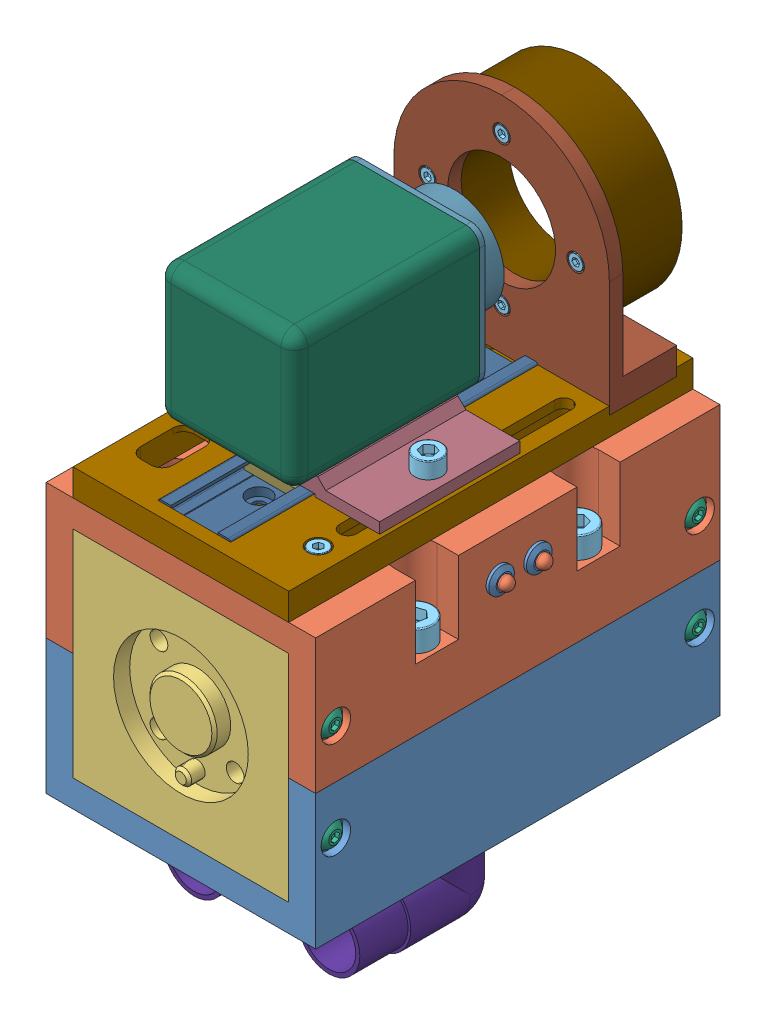
SolidWorks assembly Montagem, configuration Default. Lengths in mm.
Overall size (111.6 226.5 190.87).
85 component instances, 27 part files, 54 mates.
Components (placement in the parent):
- Conjunto-1: Conjunto [Default] at (26.1796 1.0636 35.9345) size (100.24 100 190.87)
  - Estrutura_bottom-1: Estrutura_bottom [Default] at (-19.0494 -42.1119 38.6623) size (100 50 150)
  - Estrutura_top-1: Estrutura_top [Default] at (-19.0494 47.8881 38.6623) x (-1 0 0) z (0 0 1) size (100 50 150)
  - Acoplamento_robot_50mm-1: Acoplamento_robot_50mm [Default] at (-19.0494 -2.1119 23.6623) size (80 80 15)
  - Acplamento_garra-1: Acplamento_garra [Default] at (-19.0494 -2.1119 -96.3377) size (80 80 102.04)
  - Socket Head Cap Screw_ISO-4: Socket Head Cap Screw_ISO [ISO 4762 M8 x 40 --- 28C] at (22.9506 28.8881 -6.3377) x (0 -1 0) z (-0.319372 0 -0.947629) size (48 13 13)
  - Socket Head Cap Screw_ISO-5: Socket Head Cap Screw_ISO [ISO 4762 M8 x 40 --- 28C] at (-61.0494 28.8881 -6.3377) x (0 -1 0) z (0.245168 0 0.96948) size (48 13 13)
  - Socket Head Cap Screw_ISO-6: Socket Head Cap Screw_ISO [ISO 4762 M8 x 40 --- 28C] at (22.9506 28.8881 -66.3377) x (0 -1 0) z (0.971794 0 -0.235832) size (48 13 13)
  - Socket Head Cap Screw_ISO-7: Socket Head Cap Screw_ISO [ISO 4762 M8 x 40 --- 28C] at (-61.0494 28.8881 -66.3377) x (0 -1 0) z (0 0 1) size (48 13 13)
  - Socket Button Head Screw_ISO-1: Socket Button Head Screw_ISO [ISO 7380 - M5 x 16 --- 16C] at (-68.7994 15.8881 -103.8377) x (1 0 0) z (0 -0.335428 0.942066) size (18.75 9.5 9.5)
  - Socket Button Head Screw_ISO-2: Socket Button Head Screw_ISO [ISO 7380 - M5 x 16 --- 16C] at (-68.7994 -20.1119 -103.8377) size (18.75 9.5 9.5)
  - Socket Button Head Screw_ISO-3: Socket Button Head Screw_ISO [ISO 7380 - M5 x 16 --- 16C] at (-68.7994 -20.1119 31.1623) size (18.75 9.5 9.5)
  - Socket Button Head Screw_ISO-4: Socket Button Head Screw_ISO [ISO 7380 - M5 x 16 --- 16C] at (-68.7994 15.8881 31.1623) size (18.75 9.5 9.5)
  - Socket Button Head Screw_ISO-5: Socket Button Head Screw_ISO [ISO 7380 - M5 x 16 --- 16C] at (30.7006 -20.1119 -103.8377) x (-1 0 0) z (0 -0.924225 -0.381849) size (18.75 9.5 9.5)
  - Socket Button Head Screw_ISO-6: Socket Button Head Screw_ISO [ISO 7380 - M5 x 16 --- 16C] at (30.7006 15.8881 31.1623) x (-1 0 0) z (0 -0.924225 -0.381849) size (18.75 9.5 9.5)
  - Socket Button Head Screw_ISO-7: Socket Button Head Screw_ISO [ISO 7380 - M5 x 16 --- 16C] at (30.7006 15.8881 -103.8377) x (-1 0 0) z (0 -0.924225 -0.381849) size (18.75 9.5 9.5)
  - Socket Button Head Screw_ISO-8: Socket Button Head Screw_ISO [ISO 7380 - M5 x 16 --- 16C] at (30.7006 -20.1119 31.1623) x (-1 0 0) z (0 -0.924225 -0.381849) size (18.75 9.5 9.5)
  - Socket Button Head Screw_ISO-9: Socket Button Head Screw_ISO [ISO 7380 - M5 x 16 --- 16C] at (-1.0494 -49.8619 31.1623) x (0 1 0) z (-0.188342 0 0.982104) size (18.75 9.5 9.5)
  - Socket Button Head Screw_ISO-10: Socket Button Head Screw_ISO [ISO 7380 - M5 x 16 --- 16C] at (-37.0494 -49.8619 -103.8377) x (0 1 0) z (-0.319462 0 0.947599) size (18.75 9.5 9.5)
  - Socket Button Head Screw_ISO-11: Socket Button Head Screw_ISO [ISO 7380 - M5 x 16 --- 16C] at (-1.0494 -49.8619 -103.8377) x (0 1 0) z (0.485773 0 0.874085) size (18.75 9.5 9.5)
  - Socket Button Head Screw_ISO-12: Socket Button Head Screw_ISO [ISO 7380 - M5 x 16 --- 16C] at (-37.0494 -49.8619 31.1623) x (0 1 0) z (-0.266822 0 0.963746) size (18.75 9.5 9.5)
  - Socket Button Head Screw_ISO-13: Socket Button Head Screw_ISO [ISO 7380 - M5 x 16 --- 16C] at (-1.0494 47.6381 -103.8377) x (0 -1 0) z (0 0 1) size (18.75 9.5 9.5)
  - Socket Button Head Screw_ISO-14: Socket Button Head Screw_ISO [ISO 7380 - M5 x 16 --- 16C] at (-37.1275 47.6381 -103.4453) x (0 -1 0) z (0 0 1) size (18.75 9.5 9.5)
  - Socket Button Head Screw_ISO-15: Socket Button Head Screw_ISO [ISO 7380 - M5 x 16 --- 16C] at (-37.0494 47.6381 31.1623) x (0 -1 0) z (0 0 1) size (18.75 9.5 9.5)
  - Socket Button Head Screw_ISO-16: Socket Button Head Screw_ISO [ISO 7380 - M5 x 16 --- 16C] at (-1.0494 47.6381 31.1623) x (0 -1 0) z (0 0 1) size (18.75 9.5 9.5)
  - PCB-1: PCB [Default] at (-19.0494 13.3881 -36.3377) size (66 1.5 80)
  - Slotted Cheese Head Screw_ISO-4: Slotted Cheese Head Screw_ISO [ISO 1207 - M3 x 8 --- 8C] at (10.4506 11.3881 -66.3377) x (0 1 0) z (0.99688 0 -0.078934) size (10.01 5.5 5.5)
  - Slotted Cheese Head Screw_ISO-1: Slotted Cheese Head Screw_ISO [ISO 1207 - M3 x 8 --- 8C] at (10.4506 11.3881 -6.3377) x (0 1 0) z (-0.0255 0 0.999675) size (10.01 5.5 5.5)
  - Slotted Cheese Head Screw_ISO-2: Slotted Cheese Head Screw_ISO [ISO 1207 - M3 x 8 --- 8C] at (-48.5494 11.3881 -66.3377) x (0 1 0) z (0.247102 0 -0.96899) size (10.01 5.5 5.5)
  - Slotted Cheese Head Screw_ISO-3: Slotted Cheese Head Screw_ISO [ISO 1207 - M3 x 8 --- 8C] at (-48.5494 11.3881 -6.3377) x (0 1 0) z (0.728633 0 -0.684905) size (10.01 5.5 5.5)
- Sistema_visao-1: Sistema_visao [Default] at (9.6589 51.4266 -3.453) x (-1 0 0) z (0 0 -1) size (80 99 174.57)
  - Apoio_sistema_visao-1: Apoio_sistema_visao [Default] at (2.5288 -2.475 -3.0498) size (80 10 150)
  - Calha_deslizante_27mm-1: Calha_deslizante_27mm [Default] at (2.5288 -0.475 40.9502) x (1 0 0) z (0 1 0) size (27 114 8.7)
  - Apoio_iluminacaoLEDs-1: Apoio_iluminacaoLEDs [Default] at (2.5288 47.525 45.9502) size (80 83 83.14)
  - Socket Head Cap Screw_ISO-1: Socket Head Cap Screw_ISO [ISO 4762 M4 x 12 --- 12C] at (-19.4712 14.525 55.9502) x (0 -1 0) z (-0.2501 0 -0.96822) size (16 7 7)
  - Socket Head Cap Screw_ISO-2: Socket Head Cap Screw_ISO [ISO 4762 M4 x 12 --- 12C] at (24.5288 14.525 55.9502) x (0 -1 0) z (-0.380763 0 -0.924673) size (16 7 7)
  - Carro_deslizante_27mm-1: Carro_deslizante_27mm [Default] at (2.5288 -0.525 -23.2951) x (1 0 0) z (0 1 0) size (23.9 40 5.35)
  - Apoio_camara_27mm-1: Apoio_camara_27mm [Default] at (2.5288 7.975 -43.2951) x (-1 0 0) z (0 0 -1) size (54 7 52)
  - Camara-1: Camara [Default] at (-7.4062 36.6309 -9.1632) size (50.8 57.8 84.8)
    - Encaixe_lente-1: Encaixe_lente [Default] at (9.935 10.7441 16.5114) size (50.8 50.8 16.1)
    - Carapaca-1: Carapaca [Default] at (9.935 10.7441 -17.8386) size (50.8 57.8 68.7)
  - Socket Button Head Screw_ISO-1: Socket Button Head Screw_ISO [ISO 7380 - M6 x 10 --- 10C] at (2.5288 9.575 -1.2951) x (0 1 0) z (-0.765429 0 0.643521) size (13.3 10.5 10.5)
  - Socket Button Head Screw_ISO-2: Socket Button Head Screw_ISO [ISO 7380 - M6 x 10 --- 10C] at (2.5288 9.575 -23.2951) x (0 1 0) z (0.299016 0 -0.954248) size (13.3 10.5 10.5)
  - Socket Button Head Screw_ISO-3: Socket Button Head Screw_ISO [ISO 7380 - M4 x 8 --- 8C] at (2.5288 5.275 -13.2951) x (0 1 0) z (-0.212483 0 0.977165) size (10.2 7.6 7.6)
  - Socket Button Head Screw_ISO-4: Socket Button Head Screw_ISO [ISO 7380 - M4 x 8 --- 8C] at (2.5288 5.275 -33.2951) x (0 1 0) z (-0.150761 0 0.98857) size (10.2 7.6 7.6)
  - Socket Head Cap Screw_ISO-3: Socket Head Cap Screw_ISO [ISO 4762 M6 x 12 --- 12C] at (-28.4712 17.975 -17.2951) x (0 -1 0) z (-0.981232 0 0.192829) size (18 10 10)
  - Hex Nut GradeC_ISO-1: Hex Nut GradeC_ISO [Hexagon Nut ISO - 4034 - M6 - C] at (-28.4712 4.025 -17.2951) x (1 0 0) z (0 1 0) size (10 11.55 6.1)
  - Socket Button Head Screw_ISO-6: Socket Button Head Screw_ISO [ISO 7380 - M4 x 12 --- 12C] at (2.5288 2.725 10.9502) x (0 -1 0) z (0.860915 0 -0.508749) size (14.2 7.6 7.6)
- Socket Head Cap Screw_ISO-2: Socket Head Cap Screw_ISO [ISO 4762 M4 x 16 --- 16N] at (38.1302 58.9516 54.5968) x (0 -1 0) z (-0.712267 0 0.701908) size (20 7 7)
- Socket Head Cap Screw_ISO-3: Socket Head Cap Screw_ISO [ISO 4762 M4 x 12 --- 12N] at (-23.8698 55.9516 -55.4032) x (0 -1 0) z (0 0 1) size (16 7 7)
- Conector_electrico-1: Conector_electrico [Default] at (32.0302 -46.0484 4.4968) x (0 0 1) z (1 0 0) size (52.9 41.5 25.6)
- Conector_electrico-2: Conector_electrico [Default] at (-17.9698 -46.0484 4.4968) x (0 0 1) z (1 0 0) size (52.9 41.5 25.6)
- Socket Head Cap Screw_ISO-4: Socket Head Cap Screw_ISO [ISO 4762 M2.5 x 6 --- 6N] at (22.2302 -51.0484 14.4968) x (0 1 0) z (-0.277944 0 0.960597) size (8.5 4.5 4.5)
- Socket Head Cap Screw_ISO-5: Socket Head Cap Screw_ISO [ISO 4762 M2.5 x 6 --- 6N] at (-7.9698 -51.0484 -5.3032) x (0 1 0) z (-0.277944 0 0.960597) size (8.5 4.5 4.5)
- Socket Head Cap Screw_ISO-6: Socket Head Cap Screw_ISO [ISO 4762 M2.5 x 6 --- 6N] at (22.2302 -51.0484 -5.3032) x (0 1 0) z (-0.277944 0 0.960597) size (8.5 4.5 4.5)
- Socket Head Cap Screw_ISO-7: Socket Head Cap Screw_ISO [ISO 4762 M2.5 x 6 --- 6N] at (42.0302 -51.0484 14.4968) x (0 1 0) z (-0.277944 0 0.960597) size (8.5 4.5 4.5)
- Socket Head Cap Screw_ISO-8: Socket Head Cap Screw_ISO [ISO 4762 M2.5 x 6 --- 6N] at (42.0302 -51.0484 -5.3032) x (0 1 0) z (-0.277944 0 0.960597) size (8.5 4.5 4.5)
- Socket Head Cap Screw_ISO-9: Socket Head Cap Screw_ISO [ISO 4762 M2.5 x 6 --- 6N] at (-7.9698 -51.0484 14.4968) x (0 1 0) z (-0.277944 0 0.960597) size (8.5 4.5 4.5)
- Socket Head Cap Screw_ISO-10: Socket Head Cap Screw_ISO [ISO 4762 M2.5 x 6 --- 6N] at (-27.7698 -51.0484 -5.3032) x (0 1 0) z (-0.277944 0 0.960597) size (8.5 4.5 4.5)
- Socket Head Cap Screw_ISO-11: Socket Head Cap Screw_ISO [ISO 4762 M2.5 x 6 --- 6N] at (-27.7698 -51.0484 14.4968) x (0 1 0) z (-0.277944 0 0.960597) size (8.5 4.5 4.5)
- Anel-1: Anel [Default] at (7.1302 98.9516 -49.4032) x (-1 0 0) z (0 0 -1) size (72 72 26)
- Socket Head Cap Screw_ISO-12: Socket Head Cap Screw_ISO [ISO 4762 M3 x 5 --- 5N] at (7.1302 126.4516 -44.4032) x (0 0 -1) z (0.931779 0.363027 0) size (8 5.5 5.5)
- Socket Head Cap Screw_ISO-13: Socket Head Cap Screw_ISO [ISO 4762 M3 x 5 --- 5N] at (7.1302 71.4516 -44.4032) x (0 0 -1) z (0.268788 -0.963199 0) size (8 5.5 5.5)
- Socket Head Cap Screw_ISO-14: Socket Head Cap Screw_ISO [ISO 4762 M3 x 5 --- 5N] at (-20.3698 98.9516 -44.4032) x (0 0 -1) z (0.3353 0.942111 0) size (8 5.5 5.5)
- Socket Head Cap Screw_ISO-15: Socket Head Cap Screw_ISO [ISO 4762 M3 x 5 --- 5N] at (34.6302 98.9516 -44.4032) x (0 0 -1) z (0.192392 -0.981318 0) size (8 5.5 5.5)
- LED_8mm-1: LED_8mm [Default] at (52.2812 31.651 9.4625) x (0 0.897449 0.441118) z (0 0.441118 -0.897449) size (9.5 23.85 9.5)
  - Suporte_LED-1: Suporte_LED [Default] at (0.8006 -5.901 3.5866) size (9.5 12.75 9.5)
  - LED-1: LED [Default] at (0.8006 7.449 3.5866) size (5 3.1 5)
  - Conexao-1: Conexao [Default] at (0.8006 -7.901 3.5866) x (0.063421 0 0.997987) z (-0.997987 0 0.063421) size (8 8 8)
- LED_8mm-2: LED_8mm [Default] at (52.2812 33.4745 -3.7594) x (0 0.996003 -0.089314) z (0 -0.089314 -0.996003) size (9.5 23.85 9.5)
  - Suporte_LED-1: Suporte_LED [Default] at (0.8006 -5.901 3.5866) size (9.5 12.75 9.5)
  - LED-1: LED [Default] at (0.8006 7.449 3.5866) size (5 3.1 5)
  - Conexao-1: Conexao [Default] at (0.8006 -7.901 3.5866) x (0.063421 0 0.997987) z (-0.997987 0 0.063421) size (8 8 8)
- Carapaca_topo-1: Carapaca_topo [Default] at (7.1302 48.9516 -0.4032) size (84 95 154) (hidden)
- Conjunto_sensor-1: Conjunto_sensor [Default] at (9.3235 134.4469 21.3822) x (0 0 -1) z (1 0 0) size (38 25.6 39) (hidden)
  - Placa-1: Placa [Default] at (0.0753 1.0047 -1.4363) x (0 0 -1) z (-1 0 0) size (19.9 1.5 22.1)
  - Sensor-1: Sensor [Default] at (0.0753 1.9047 -0.3263) x (0 0 1) z (-1 0 0) size (15.5 18 15.5)
  - Base-1: Base [Default] at (-4.3747 -5.4953 -1.4863) size (38 9.5 39)
  - Tampa2-1: Tampa2 [Default] at (-4.3747 13.0047 -1.4863) x (1 0 0) z (0 0 -1) size (38 15.5 27)
  - LED_8mm-1: LED_8mm [Default] at (-16.7253 10.1557 0.0871) size (9.5 23.85 9.5)
    - Suporte_LED-1: Suporte_LED [Default] at (0.8006 -5.901 3.5866) size (9.5 12.75 9.5)
    - LED-1: LED [Default] at (0.8006 7.449 3.5866) size (5 3.1 5)
    - Conexao-1: Conexao [Default] at (0.8006 -7.901 3.5866) x (0.063421 0 0.997987) z (-0.997987 0 0.063421) size (8 8 8)
- Ventoinha-1: Ventoinha [Default] at (-46.8698 18.9516 -0.4032) x (0 1 0) z (1 0 0) size (25 25 10)
- Socket Head Cap Screw_ISO-17: Socket Head Cap Screw_ISO [ISO 4762 M2.5 x 16 --- 16C] at (-49.3698 28.9516 9.5968) x (1 0 0) z (0 0.619223 0.785215) size (18.5 4.5 4.5)
Mates (geometry in assembly coordinates):
- Concentric1: concentric aligned: cylinder of Conjunto-1/Estrutura_top-1 through (-23.8698 48.9516 -55.4032) axis (0 1 0) radius 1.65; cylinder of Sistema_visao-1/Apoio_sistema_visao-1 through (-23.8698 55.9516 -55.4032) axis (0 1 0) radius 2.4
- Concentric2: concentric aligned: cylinder of Conjunto-1/Estrutura_top-1 through (38.1302 48.9516 54.5968) axis (0 1 0) radius 1.65; cylinder of Sistema_visao-1/Apoio_sistema_visao-1 through (38.1302 58.9516 54.5968) axis (0 1 0) radius 2.4
- Coincident1: coincident anti-aligned: plane of Conjunto-1/Estrutura_top-1 through (57.1302 48.9516 -75.4032) normal (0 1 0); plane of Sistema_visao-1/Apoio_sistema_visao-1 through (47.1302 48.9516 -75.4032) normal (0 -1 0)
- Concentric3: concentric aligned: cylinder of Conjunto-1/Estrutura_top-1 through (38.1302 48.9516 54.5968) axis (0 1 0) radius 1.65; cylinder of Socket Head Cap Screw_ISO-2 through (38.1302 90.7016 54.5968) axis (0 1 0) radius 2
- Concentric4: concentric aligned: cylinder of Conjunto-1/Estrutura_top-1 through (-23.8698 48.9516 -55.4032) axis (0 1 0) radius 1.65; cylinder of Socket Head Cap Screw_ISO-3 through (-23.8698 87.7016 -55.4032) axis (0 1 0) radius 2
- Coincident2: coincident anti-aligned: plane of Sistema_visao-1/Apoio_sistema_visao-1 through (-26.2698 51.9516 -55.4032) normal (0 1 0); plane of Socket Head Cap Screw_ISO-3 through (-20.3698 51.9516 -55.4032) normal (0 -1 0)
- Coincident3: coincident anti-aligned: plane of Sistema_visao-1/Apoio_sistema_visao-1 through (35.7302 54.9516 54.5968) normal (0 1 0); plane of Socket Head Cap Screw_ISO-2 through (40.5869 54.9516 57.0898) normal (0 -1 0)
- Concentric7: concentric aligned: cylinder of Conjunto-1/Estrutura_bottom-1 through (-7.9698 -51.0484 -5.3032) axis (0 -1 0) radius 1.025; cylinder of Conector_electrico-2 through (-7.9698 -48.5484 -5.3032) axis (0 -1 0) radius 1.35
- Concentric9: concentric aligned: cylinder of Conjunto-1/Estrutura_bottom-1 through (-27.7698 -51.0484 14.4968) axis (0 -1 0) radius 1.025; cylinder of Conector_electrico-2 through (-27.7698 -48.5484 14.4968) axis (0 -1 0) radius 1.35
- Coincident4: coincident anti-aligned: plane of Conjunto-1/Estrutura_bottom-1 through (-32.8698 -46.0484 -15.4032) normal (0 -1 0); plane of Conector_electrico-2 through (-5.1698 -46.0484 -8.3032) normal (0 1 0)
- Concentric10: concentric aligned: cylinder of Conjunto-1/Estrutura_bottom-1 through (42.0302 -51.0484 -5.3032) axis (0 -1 0) radius 1.025; cylinder of Conector_electrico-1 through (42.0302 -48.5484 -5.3032) axis (0 -1 0) radius 1.35
- Concentric11: concentric aligned: cylinder of Conjunto-1/Estrutura_bottom-1 through (22.2302 -51.0484 14.4968) axis (0 -1 0) radius 1.025; cylinder of Conector_electrico-1 through (22.2302 -48.5484 14.4968) axis (0 -1 0) radius 1.35
- Coincident5: coincident anti-aligned: plane of Conjunto-1/Estrutura_bottom-1 through (-32.8698 -46.0484 -15.4032) normal (0 -1 0); plane of Conector_electrico-1 through (44.8302 -46.0484 -8.3032) normal (0 1 0)
- Concentric12: concentric aligned: cylinder of Conjunto-1/Estrutura_bottom-1 through (42.0302 -51.0484 14.4968) axis (0 -1 0) radius 1.025; cylinder of Socket Head Cap Screw_ISO-7 through (42.0302 -82.7984 14.4968) axis (0 -1 0) radius 1.25
- Coincident6: coincident anti-aligned: plane of Conector_electrico-1 through (44.8302 -48.5484 -8.3032) normal (0 -1 0); plane of Socket Head Cap Screw_ISO-7 through (39.8688 -48.5484 13.8715) normal (0 1 0)
- Concentric13: concentric aligned: cylinder of Conjunto-1/Estrutura_bottom-1 through (42.0302 -51.0484 -5.3032) axis (0 -1 0) radius 1.025; cylinder of Socket Head Cap Screw_ISO-8 through (42.0302 -82.7984 -5.3032) axis (0 -1 0) radius 1.25
- Coincident7: coincident anti-aligned: plane of Conector_electrico-1 through (44.8302 -48.5484 -8.3032) normal (0 -1 0); plane of Socket Head Cap Screw_ISO-8 through (39.8688 -48.5484 -5.9285) normal (0 1 0)
- Concentric14: concentric aligned: cylinder of Conjunto-1/Estrutura_bottom-1 through (22.2302 -51.0484 14.4968) axis (0 -1 0) radius 1.025; cylinder of Socket Head Cap Screw_ISO-4 through (22.2302 -82.7984 14.4968) axis (0 -1 0) radius 1.25
- Coincident8: coincident anti-aligned: plane of Conector_electrico-1 through (44.8302 -48.5484 -8.3032) normal (0 -1 0); plane of Socket Head Cap Screw_ISO-4 through (20.0688 -48.5484 13.8715) normal (0 1 0)
- Concentric15: concentric aligned: cylinder of Conjunto-1/Estrutura_bottom-1 through (22.2302 -51.0484 -5.3032) axis (0 -1 0) radius 1.025; cylinder of Socket Head Cap Screw_ISO-6 through (22.2302 -82.7984 -5.3032) axis (0 -1 0) radius 1.25
- Coincident9: coincident anti-aligned: plane of Conector_electrico-1 through (44.8302 -48.5484 -8.3032) normal (0 -1 0); plane of Socket Head Cap Screw_ISO-6 through (20.0688 -48.5484 -5.9285) normal (0 1 0)
- Concentric16: concentric aligned: cylinder of Conjunto-1/Estrutura_bottom-1 through (-7.9698 -51.0484 -5.3032) axis (0 -1 0) radius 1.025; cylinder of Socket Head Cap Screw_ISO-5 through (-7.9698 -82.7984 -5.3032) axis (0 -1 0) radius 1.25
- Coincident10: coincident anti-aligned: plane of Conector_electrico-2 through (-5.1698 -48.5484 -8.3032) normal (0 -1 0); plane of Socket Head Cap Screw_ISO-5 through (-10.1312 -48.5484 -5.9285) normal (0 1 0)
- Concentric17: concentric aligned: cylinder of Conjunto-1/Estrutura_bottom-1 through (-7.9698 -51.0484 14.4968) axis (0 -1 0) radius 1.025; cylinder of Socket Head Cap Screw_ISO-9 through (-7.9698 -82.7984 14.4968) axis (0 -1 0) radius 1.25
- Coincident11: coincident anti-aligned: plane of Conector_electrico-2 through (-5.1698 -48.5484 -8.3032) normal (0 -1 0); plane of Socket Head Cap Screw_ISO-9 through (-10.1312 -48.5484 13.8715) normal (0 1 0)
- Concentric18: concentric aligned: circle of Conjunto-1/Estrutura_bottom-1; cylinder of Socket Head Cap Screw_ISO-10 through (-27.7698 -82.7984 -5.3032) axis (0 -1 0) radius 1.25
- Coincident12: coincident anti-aligned: plane of Conector_electrico-2 through (-5.1698 -48.5484 -8.3032) normal (0 -1 0); plane of Socket Head Cap Screw_ISO-10 through (-29.9312 -48.5484 -5.9285) normal (0 1 0)
- Concentric19: concentric aligned: cylinder of Conjunto-1/Estrutura_bottom-1 through (-27.7698 -51.0484 14.4968) axis (0 -1 0) radius 1.025; cylinder of Socket Head Cap Screw_ISO-11 through (-27.7698 -82.7984 14.4968) axis (0 -1 0) radius 1.25
- Coincident13: coincident aligned: plane of Conector_electrico-2 through (-5.1698 -48.5484 -8.3032) normal (0 -1 0); circle of Socket Head Cap Screw_ISO-11
- Concentric20: concentric aligned: cylinder of Sistema_visao-1/Apoio_iluminacaoLEDs-1 through (-20.3698 98.9516 -44.4032) axis (0 0 1) radius 1.7; cylinder of Anel-1 through (-20.3698 98.9516 -49.4032) axis (0 0 1) radius 1.25
- Concentric21: concentric aligned: cylinder of Sistema_visao-1/Apoio_iluminacaoLEDs-1 through (34.6302 98.9516 -44.4032) axis (0 0 1) radius 1.7; cylinder of Anel-1 through (34.6302 98.9516 -49.4032) axis (0 0 1) radius 1.25
- Coincident14: coincident anti-aligned: plane of Sistema_visao-1/Apoio_iluminacaoLEDs-1 through (47.1302 55.9516 -49.4032) normal (0 0 -1); plane of Anel-1 through (7.1302 98.9516 -49.4032) normal (0 0 1)
- Concentric22: concentric aligned: cylinder of Anel-1 through (7.1302 126.4516 -49.4032) axis (0 0 1) radius 1.25; cylinder of Socket Head Cap Screw_ISO-12 through (7.1302 126.4516 -12.6532) axis (0 0 1) radius 1.5
- Concentric23: concentric aligned: cylinder of Anel-1 through (34.6302 98.9516 -49.4032) axis (0 0 1) radius 1.25; cylinder of Socket Head Cap Screw_ISO-15 through (34.6302 98.9516 -12.6532) axis (0 0 1) radius 1.5
- Concentric24: concentric aligned: cylinder of Anel-1 through (7.1302 71.4516 -49.4032) axis (0 0 1) radius 1.25; cylinder of Socket Head Cap Screw_ISO-13 through (7.1302 71.4516 -12.6532) axis (0 0 1) radius 1.5
- Concentric25: concentric aligned: cylinder of Anel-1 through (-20.3698 98.9516 -49.4032) axis (0 0 1) radius 1.25; cylinder of Socket Head Cap Screw_ISO-14 through (-20.3698 98.9516 -12.6532) axis (0 0 1) radius 1.5
- Coincident15: coincident anti-aligned: plane of Sistema_visao-1/Apoio_iluminacaoLEDs-1 through (5.4302 71.4516 -47.4032) normal (0 0 1); plane of Socket Head Cap Screw_ISO-13 through (9.779 72.1908 -47.4032) normal (0 0 -1)
- Coincident17: coincident anti-aligned: plane of Sistema_visao-1/Apoio_iluminacaoLEDs-1 through (32.9302 98.9516 -47.4032) normal (0 0 1); plane of Socket Head Cap Screw_ISO-15 through (37.3288 99.4807 -47.4032) normal (0 0 -1)
- Coincident18: coincident anti-aligned: plane of Sistema_visao-1/Apoio_iluminacaoLEDs-1 through (5.4302 126.4516 -47.4032) normal (0 0 1); plane of Socket Head Cap Screw_ISO-12 through (6.1319 129.014 -47.4032) normal (0 0 -1)
- Coincident19: coincident anti-aligned: plane of Sistema_visao-1/Apoio_iluminacaoLEDs-1 through (-22.0698 98.9516 -47.4032) normal (0 0 1); plane of Socket Head Cap Screw_ISO-14 through (-22.9606 99.8737 -47.4032) normal (0 0 -1)
- Concentric27: concentric anti-aligned: cylinder of Conjunto-1/Estrutura_top-1 through (57.1302 33.9516 -7.4032) axis (1 0 0) radius 3.4; cylinder of LED_8mm-2/Suporte_LED-1 through (22.3687 33.9516 -7.4032) axis (-1 0 0) radius 4
- Concentric28: concentric anti-aligned: cylinder of Conjunto-1/Estrutura_top-1 through (57.1302 33.9516 6.5968) axis (1 0 0) radius 3.4; cylinder of LED_8mm-1/Suporte_LED-1 through (22.3687 33.9516 6.5968) axis (-1 0 0) radius 4
- Coincident20: coincident anti-aligned: plane of Conjunto-1/Estrutura_top-1 through (57.1302 -1.0484 -75.4032) normal (1 0 0); plane of LED_8mm-1/Suporte_LED-1 through (57.1302 38.2145 8.6922) normal (-1 0 0)
- Coincident21: coincident anti-aligned: plane of Conjunto-1/Estrutura_top-1 through (57.1302 -1.0484 -75.4032) normal (1 0 0); plane of LED_8mm-2/Suporte_LED-1 through (57.1302 38.6826 -7.8274) normal (-1 0 0)
- Coincident22: coincident anti-aligned: plane of Sistema_visao-1/Apoio_sistema_visao-1 through (-32.8698 58.9516 74.5968) normal (-1 0 0); plane of Carapaca_topo-1 through (-32.8698 143.9516 -77.4032) normal (1 0 0)
- Coincident23: coincident anti-aligned: plane of Sistema_visao-1/Apoio_sistema_visao-1 through (47.1302 58.9516 74.5968) normal (0 0 1); plane of Carapaca_topo-1 through (-34.8698 143.9516 74.5968) normal (0 0 -1)
- Coincident24: coincident anti-aligned: plane of Conjunto-1/Estrutura_top-1 through (57.1302 48.9516 -75.4032) normal (0 1 0); plane of Carapaca_topo-1 through (49.1302 48.9516 76.5968) normal (0 -1 0)
- Coincident25: coincident anti-aligned: plane of Carapaca_topo-1 through (-34.8698 128.9516 -38.4032) normal (0 1 0); plane of Conjunto_sensor-1/Base-1 through (21.3372 128.9516 44.7569) normal (0 -1 0)
- Parallel1: parallel anti-aligned: line of Carapaca_topo-1 through (43.3017 128.9516 74.5968) axis (0 0 -1); line of Conjunto_sensor-1/Base-1 through (27.3372 128.9516 8.7569) axis (0 0 1)
- Concentric29: concentric anti-aligned: cylinder of Conjunto-1/Estrutura_top-1 through (-36.8698 28.9516 9.5968) axis (-1 0 0) radius 1.025; cylinder of Ventoinha-1 through (-36.8698 28.9516 9.5968) axis (1 0 0) radius 1.4
- Concentric30: concentric anti-aligned: cylinder of Conjunto-1/Estrutura_top-1 through (-36.8698 8.9516 -10.4032) axis (-1 0 0) radius 1.025; cylinder of Ventoinha-1 through (-36.8698 8.9516 -10.4032) axis (1 0 0) radius 1.4
- Coincident26: coincident anti-aligned: plane of Conjunto-1/Estrutura_top-1 through (-36.8698 31.9516 -13.4032) normal (-1 0 0); plane of Ventoinha-1 through (-36.8698 31.4516 -12.9032) normal (1 0 0)
- Concentric31: concentric aligned: cylinder of Conjunto-1/Estrutura_top-1 through (-36.8698 28.9516 9.5968) axis (-1 0 0) radius 1.025; cylinder of Socket Head Cap Screw_ISO-17 through (-81.1198 28.9516 9.5968) axis (-1 0 0) radius 1.25
- Coincident28: coincident anti-aligned: plane of Ventoinha-1 through (-46.8698 31.4516 -12.9032) normal (-1 0 0); plane of Socket Head Cap Screw_ISO-17 through (-46.8698 30.7183 8.2036) normal (1 0 0)
